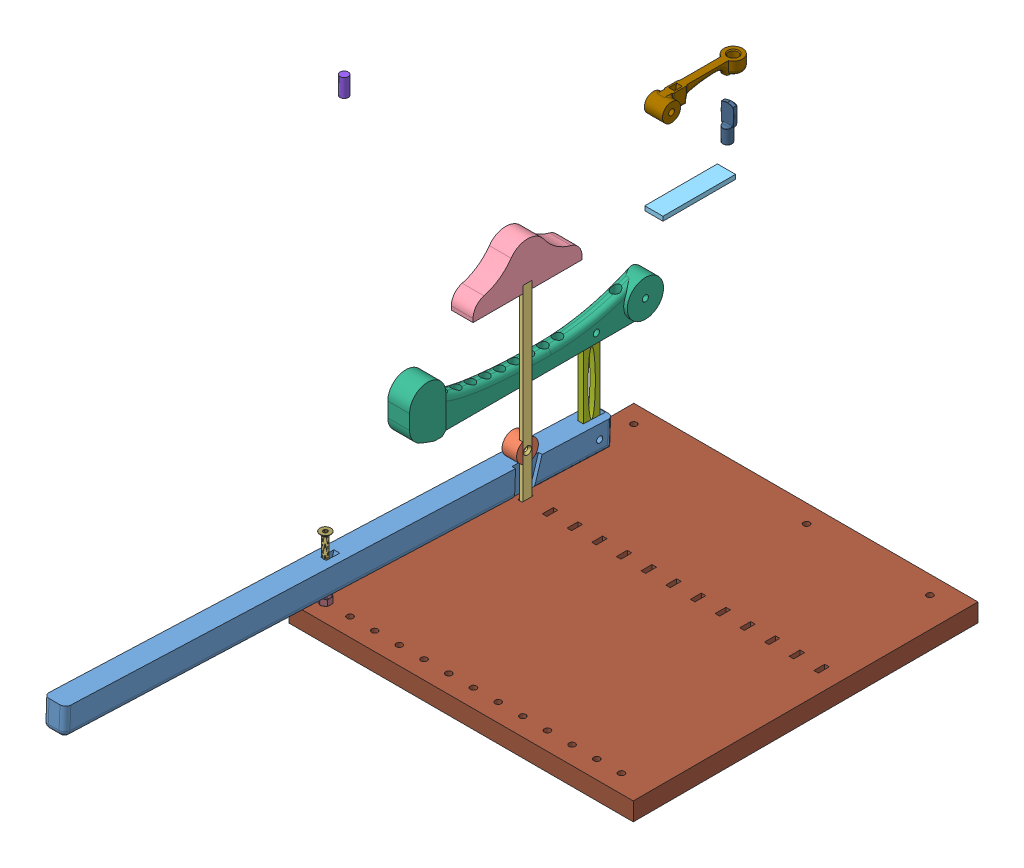
SolidWorks assembly Clavi Action, configuration Default. Lengths in mm.
Overall size (306.69 231.02 395.28).
13 component instances, 13 part files, 19 mates.
Components (placement in the parent):
- Keylever-1: Keylever [Default] at (18.7139 -42.4132 121.7276) x (1 0 0) z (0 0.03955 0.999218) size (12 15 302.5)
- Damper Rod Guide-1: Damper Rod Guide [Default] at (23.1139 -25.5528 16.7276) size (8 12 12)
- Damper Rod-1: Damper Rod [Default] at (23.1139 52.4472 14.2276) size (10 200 5)
- Damper-1: Damper [Default] at (23.1139 50.4472 46.7276) size (12 25 60)
- Felt Piece-1: Felt Piece [Default] at (21.5542 52.9558 -51.4904) size (10 2.4 40)
- Hammer-1: Hammer [Default] at (18.9139 14.3461 -48.4556) size (12 30 140)
- Linkage-1: Linkage [Default] at (17.3139 -40.6539 -23.4556) size (3 59 9)
- Pickup Magnet-1: Pickup Magnet [Default] at (-106.0281 73.3821 -13.3743) size (4.5 10 4.5)
- Tangent Arm-1: Tangent Arm [Default] at (3.2235 80.2611 -78.5652) size (11.1 10.21 50.1)
- Tangent-1: Tangent [Default] at (12.6064 62.3591 -105.9584) size (7 18.6 6.4)
- Action base-1: Action base [Default] at (18.7139 -48.6996 121.7276) size (189.7 10 190)
- 91294A141_Black-Oxide Alloy Steel Hex Drive Flat Head Screw-1: 91294A141_Black-Oxide Alloy Steel Hex Drive Flat Head Screw [91294A141] at (18.7139 -29.7586 121.7276) x (1 0 0) z (0 1 0) size (6 6 30.35)
- 93625A100_18-8 Stainless Steel Nylon-Insert Locknut-1: 93625A100_18-8 Stainless Steel Nylon-Insert Locknut [93625A100] at (18.7139 -46.6996 121.7276) x (-1 0 0) z (0 0 -1) size (5.52 4.11 6.32)
Mates (geometry in assembly coordinates):
- Coincident2: coincident anti-aligned: plane of Damper Rod-1 through (25.1139 54.4472 19.2276) normal (0 1 0); plane of Damper-1 through (13.1139 54.4472 9.9603) normal (0 -1 0)
- Coincident3: coincident anti-aligned: plane of Damper Rod-1 through (23.1139 52.4472 19.2276) normal (-1 0 0); plane of Damper-1 through (23.1139 52.4472 29.2651) normal (1 0 0)
- Coincident5: coincident anti-aligned: plane of Damper Rod Guide-1 through (23.1139 -25.5528 16.7276) normal (1 0 0); plane of Damper Rod-1 through (23.1139 52.4472 19.2276) normal (-1 0 0)
- Concentric1: concentric aligned: cylinder of Damper Rod Guide-1 through (23.1139 -25.5528 16.7276) axis (1 0 0) radius 1.1; cylinder of Damper Rod-1 through (25.1139 -25.5528 16.7276) axis (1 0 0) radius 1.1
- Parallel1: parallel anti-aligned: plane of Damper Rod Guide-1 through (25.1139 -20.1454 19.3276) normal (0 0 -1); plane of Damper Rod-1 through (23.1139 52.4472 19.2276) normal (0 0 1)
- Tangent1: tangent anti-aligned: cylinder of Damper Rod Guide-1 through (17.1139 -25.5528 16.7276) axis (1 0 0) radius 6; plane of Keylever-1 through (22.2139 -27.425 121.1343) normal (0 0.999218 -0.03955)
- Concentric2: concentric anti-aligned: cylinder of Linkage-1 through (20.3139 -40.6539 -23.4556) axis (-1 0 0) radius 1.6; cylinder of Keylever-1 through (12.7139 -40.6539 -23.4556) axis (1 0 0) radius 1.7
- Distance1: distance = 0.1 mm anti-aligned: plane of Linkage-1 through (20.3139 -40.6539 -23.4556) normal (1 0 0); plane of Keylever-1 through (20.4139 -40.6539 -23.4556) normal (-1 0 0)
- Concentric3: concentric aligned: cylinder of Hammer-1 through (22.9139 9.3461 -23.4556) axis (-1 0 0) radius 1.7; cylinder of Linkage-1 through (20.3139 9.3461 -23.4556) axis (-1 0 0) radius 1.6
- Distance2: distance = 0.1 mm anti-aligned: plane of Hammer-1 through (17.2139 9.3461 -23.4556) normal (1 0 0); plane of Linkage-1 through (17.3139 -40.6539 -23.4556) normal (-1 0 0)
- Distance3: distance = 0.1 mm anti-aligned: plane of Damper Rod-1 through (25.1139 -145.5528 19.2276) normal (1 0 0); plane of Action base-1 through (25.2139 -58.6996 121.7276) normal (-1 0 0)
- Distance4: distance = 0.5 mm anti-aligned: plane of Action base-1 through (18.7139 -58.6996 13.7276) normal (0 0 1); plane of Damper Rod-1 through (23.1139 52.4472 14.2276) normal (0 0 -1)
- Concentric4: concentric anti-aligned: cylinder of Action base-1 through (18.7139 -58.6996 121.7276) axis (0 1 0) radius 1.7; cylinder of 91294A141_Black-Oxide Alloy Steel Hex Drive Flat Head Screw-1 through (18.7139 -44.7586 121.7276) axis (0 -1 0) radius 1.5
- Concentric5: concentric aligned: cylinder of 91294A141_Black-Oxide Alloy Steel Hex Drive Flat Head Screw-1 through (18.7139 -44.7586 121.7276) axis (0 -1 0) radius 1.5; cylinder of 93625A100_18-8 Stainless Steel Nylon-Insert Locknut-1 through (18.7139 -44.6996 121.7276) axis (0 -1 0) radius 1.5
- Coincident7: coincident anti-aligned: plane of Action base-1 through (18.7139 -48.6996 121.7276) normal (0 1 0); plane of 93625A100_18-8 Stainless Steel Nylon-Insert Locknut-1 through (18.7139 -48.6996 121.7276) normal (0 -1 0)
- Coincident9: coincident: line of assembly; point of Keylever-1; line of 91294A141_Black-Oxide Alloy Steel Hex Drive Flat Head Screw-1 through (18.7139 -44.7586 121.7276) axis (0 1 0)
- Coincident12: coincident: circle of Keylever-1
- Parallel3: parallel anti-aligned: plane of Keylever-1 through (22.7139 -42.4132 121.7276) normal (1 0 0); plane of Damper Rod-1 through (23.1139 52.4472 19.2276) normal (-1 0 0)
- Distance8: distance = 0.1 mm anti-aligned: plane of Damper-1 through (13.1139 52.4472 14.1276) normal (0 0 1); plane of Damper Rod-1 through (23.1139 52.4472 14.2276) normal (0 0 -1)
